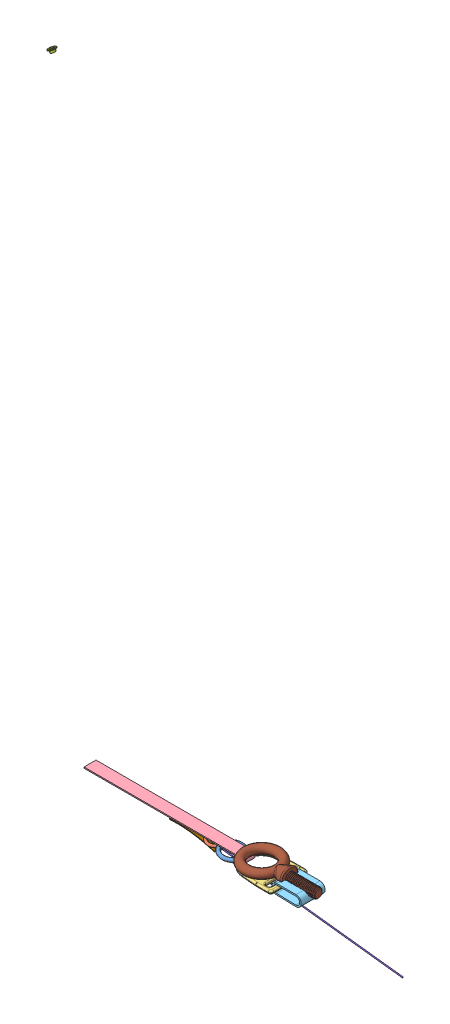
SolidWorks assembly 3-ring_assy.1, configuration Default. Lengths in mm.
Overall size (539.64 769.93 100.15).
11 component instances, 11 part files, 29 mates.
Components (placement in the parent):
- No.3_ring-1: No.3_ring [Default] at (-72.1045 -9.3447 0.1604) x (0 0 1) z (0.100747 0.994912 0) size (31.35 31.35 4.56)
- No.4_ring-1: No.4_ring [Default] at (-101.1259 -8.5542 0.1604) x (0 0 1) z (0.144178 0.989552 0) size (20.24 20.24 3.37)
- No.10_ring-1: No.10_ring [Default] at (-68.582 -6.608 0) x (0 0 -1) z (0 1 0) size (50.48 61.82 4.57)
- Webbing_mid-1: Webbing_mid [Default] at (-172.8323 -1.8956 0) x (1 0 0) z (0 0 -1) size (211.94 13.13 15.88)
- Webbing_main-1: Webbing_main [Default] x (-1 0 0) z (0 0 1) size (39.18 13.97 31.75)
- Webbing_top-2: Webbing_top [Default] at (-122.6786 -3.4196 0.1604) x (1 0 0) z (0 0 -1) size (91.79 8.45 9.53)
- grommet-1: grommet [Default] at (-392.3243 722.7478 -68.8714) x (0.888305 0.459251 0.001711) z (0 -0.003727 0.999993) size (10.16 4.19 10.16)
- yellow_cord-1: yellow_cord [Default] at (140.7757 -40.2362 0) x (-0.062438 -0.534312 -0.842978) z (0.097842 0.837281 -0.537947) size (1.27 304.8 1.27)
- grommet_webbing-1: grommet_webbing [Default] at (-131.8234 -2.5368 -7.9375) x (-0.064683 0.997906 0) z (0 0 1) size (12.82 58.93 15.88)
- nylon_loop.1-1: nylon_loop.1 [Default] at (-111.1356 -13.0989 0) x (0 0 1) z (-0.116067 -0.993241 0) size (2.98 3.17 7.87)
- 8891T790_316 STAINLESS STEEL EYEBOLT-1: 8891T790_316 STAINLESS STEEL EYEBOLT [8891T79] at (-46.4457 0 0) x (0 0 1) z (0 -1 0) size (52.39 102.35 23.02)
Mates (geometry in assembly coordinates):
- Coincident65: coincident: plane of Webbing_main-1 through (0 0 0) normal (0 0 1); plane of assembly through (0 0 0) normal (0 0 1)
- Coincident66: coincident: plane of Webbing_main-1 through (0 0 0) normal (-1 0 0); plane of assembly through (0 0 0) normal (1 0 0)
- Coincident67: coincident: plane of Webbing_main-1 through (0 0 0) normal (0 -1 0); plane of assembly through (0 0 0) normal (0 1 0)
- Coincident68: coincident: line of No.10_ring-1 through (-15.4008 -6.608 17.9387) axis (0 0 -1); point of Webbing_main-1
- Coincident69: coincident: plane of No.10_ring-1 through (-15.4008 -4.322 17.9387) normal (-1 0 0); point of Webbing_main-1
- Parallel27: parallel: plane of No.10_ring-1 through (-15.4008 -4.322 17.9387) normal (-1 0 0); plane of assembly through (0 0 0) normal (1 0 0)
- Coincident71: coincident: plane of No.10_ring-1 through (-68.582 -6.608 0) normal (0 0 -1); plane of assembly through (0 0 0) normal (0 0 1)
- Parallel29: parallel: plane of Webbing_mid-1 through (-172.8323 -1.8956 0) normal (0 1 0); plane of Webbing_main-1 through (0 0 0) normal (0 1 0)
- Parallel30: parallel: plane of Webbing_mid-1 through (-172.8323 -1.8956 0) normal (0 0 -1); plane of assembly through (0 0 0) normal (0 0 1)
- Coincident77: coincident: point of No.10_ring-1; point of Webbing_mid-1
- Coincident79: coincident: point of No.3_ring-1; point of Webbing_mid-1
- Coincident81: coincident: line of No.3_ring-1 through (-77.5337 -8.795 7.9375) axis (0 0 -1); point of Webbing_mid-1
- Coincident82: coincident: point of No.3_ring-1; point of Webbing_top-2
- Coincident83: coincident: plane of Webbing_mid-1 through (-172.8323 -3.4196 0) normal (0 -1 0); plane of Webbing_top-2 through (-122.6786 -3.4196 0.1604) normal (0 1 0)
- Parallel31: parallel: plane of Webbing_mid-1 through (-274.4323 -3.4196 7.9375) normal (0 0 1); plane of Webbing_top-2 through (-186.1786 -4.4356 4.9229) normal (0 0 1)
- Coincident84: coincident: line of No.3_ring-1 through (-95.42 -6.9838 4.9229) axis (0 0 -1); point of Webbing_top-2
- Coincident85: coincident: point of No.4_ring-1; point of Webbing_top-2
- Coincident88: coincident: point of No.4_ring-1; point of Webbing_top-2
- Tangent33: tangent: torus of No.4_ring-1; plane of Webbing_top-2 through (-122.6786 -4.4356 0.1604) normal (0 -1 0)
- Coincident89: coincident: plane of Webbing_top-2 through (-122.6786 -4.4356 0.1604) normal (0 -1 0); line of grommet_webbing-1 through (-161.1172 -4.4356 7.9375) axis (0 0 -1)
- Coincident91: coincident: plane of Webbing_main-1 through (0 0 0) normal (0 0 1); plane of grommet_webbing-1 through (-131.8234 -2.5368 0) normal (0 0 1)
- Coincident92: coincident: point of No.4_ring-1; face of grommet_webbing-1
- Angle3: planar angle = 3.316126 rad: cylinder of grommet_webbing-1 through (-116.8311 -30.2415 0) axis (0.286779 0.957997 0) radius 2.3813; line of nylon_loop.1-1 through (-110.8998 -11.0807 0) axis (-0.116067 -0.993241 0)
- Coincident94: coincident: plane of grommet_webbing-1 through (-131.8234 -2.5368 0) normal (0 0 1); plane of nylon_loop.1-1 through (-111.1356 -13.0989 0) normal (0 0 1)
- Coincident95: coincident: point of grommet_webbing-1; plane of nylon_loop.1-1 through (-110.7741 -10.0055 0) normal (0.116067 0.993241 0)
- Concentric2: concentric: cylinder of yellow_cord-1 through (-161.9643 -4.8588 0) axis (0.993241 -0.116067 0) radius 0.635; cylinder of nylon_loop.1-1 through (-109.2936 -11.0137 0) axis (-0.993241 0.116067 0) radius 0.762
- Coincident96: coincident: point of grommet_webbing-1; line of nylon_loop.1-1 through (-110.8998 -11.0807 0) axis (-0.116067 -0.993241 0)
- Coincident97: coincident: plane of 8891T790_316 STAINLESS STEEL EYEBOLT-1 through (-46.4457 0 0) normal (0 -1 0); plane of assembly through (0 0 0) normal (0 1 0)
- Coincident98: coincident: plane of 8891T790_316 STAINLESS STEEL EYEBOLT-1 through (-46.4457 0 0) normal (0 0 1); plane of assembly through (0 0 0) normal (0 0 1)
